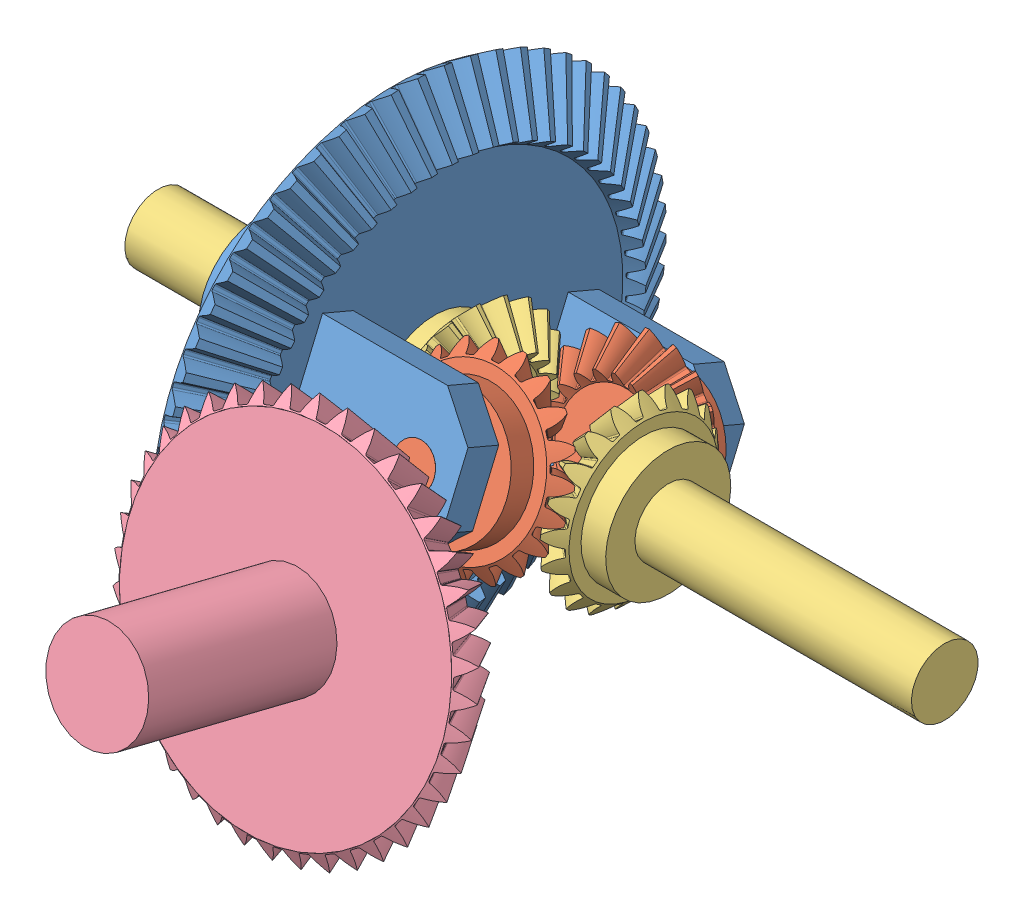
SolidWorks assembly Differential Assembly, configuration Default. Lengths in mm.
Overall size (471.43 398.88 514.12).
7 component instances, 5 part files, 17 mates.
Components (placement in the parent):
- G 60-1: G 60 [Default] at (14.6727 184.1865 258.052) x (1 0 0) z (0 -0.920286 0.391245) size (198.85 304.13 304.13)
- G 20.1-1: G 20.1 [Default] at (108.5266 185.9313 262.156) x (0 -0.391245 -0.920286) z (0.04196 -0.919476 0.390901) size (61.23 106.69 106.69)
- G 20.1-2: G 20.1 [Default] at (108.5266 182.4418 253.9479) x (0 0.391245 0.920286) z (-0.04196 -0.919476 0.390901) size (61.23 106.69 106.69)
- G 20.2-1: G 20.2 [Default] at (104.067 184.1865 258.052) x (1 0 0) z (0 -0.412672 0.91088) size (206.95 106.69 106.69)
- G 20.2-2: G 20.2 [Default] at (112.9861 184.1865 258.052) x (-1 0 0) z (0 -0.334846 0.942273) size (206.95 106.69 106.69)
- Part3^Differential Assembly-1: Part3^Differential Assembly [Default] at origin size (350 434.54 490.09) (hidden, virtual)
- G 40-1: G 40 [Default] at (115.3737 179.9131 424.2516) x (0 -0.241209 -0.970473) z (0.825408 -0.547868 0.136172) size (157.05 212.76 212.76)
Mates (geometry in assembly coordinates):
- Coincident1: coincident aligned: circle of G 60-1; circle of G 20.1-1
- Coincident2: coincident aligned: circle of G 60-1; circle of G 20.1-2
- Coincident3: coincident anti-aligned: circle of G 60-1; circle of G 20.2-1
- Concentric2: concentric anti-aligned: cylinder of G 20.2-1 through (-127.1902 184.1865 258.052) axis (1 0 0) radius 20; cylinder of G 20.2-2 through (344.2434 184.1865 258.052) axis (-1 0 0) radius 20
- Distance3: distance = 140 mm aligned: plane of G 60-1 through (38.5266 184.1865 258.052) normal (1 0 0); plane of G 20.2-2 through (178.5266 184.1865 258.052) normal (1 0 0)
- Parallel1: parallel aligned: unknown of G 20.1-1
- Parallel4: parallel aligned: plane of G 20.1-2 through (108.5266 182.4418 253.9479) normal (-0.04196 -0.919476 0.390901)
- Angle1: planar angle = 0.785398 rad: plane of assembly through (0 0 0) normal (0 0 1); plane of G 20.2-1 through (104.067 184.1865 258.052) normal (0 -0.412672 0.91088); plane of assembly
- Angle2: planar angle = 0.785398 rad: plane of assembly through (0 0 0) normal (0 0 1); plane of assembly; plane of G 20.2-2 through (112.9861 184.1865 258.052) normal (0 -0.334846 0.942273)
- GearMate1: gear = 75 : 75 mm: cylinder of G 20.2-2 through (178.5266 184.1865 258.052) axis (-1 0 0) radius 37.5; cylinder of G 20.1-1 through (108.5266 211.5737 322.472) axis (0 -0.391245 -0.920286) radius 37.5
- GearMate2: gear = 75 : 75 mm: cylinder of G 20.1-1 through (108.5266 211.5737 322.472) axis (0 -0.391245 -0.920286) radius 37.5; cylinder of G 20.2-1 through (38.5266 184.1865 258.052) axis (1 0 0) radius 37.5
- GearMate3: gear = 75 : 75 mm: cylinder of G 20.2-2 through (178.5266 184.1865 258.052) axis (-1 0 0) radius 37.5; cylinder of G 20.1-2 through (108.5266 156.7994 193.6319) axis (0 0.391245 0.920286) radius 37.5
- GearMate4: gear = 75 : 75 mm: cylinder of G 20.2-1 through (38.5266 184.1865 258.052) axis (1 0 0) radius 37.5; cylinder of G 20.1-2 through (108.5266 156.7994 193.6319) axis (0 0.391245 0.920286) radius 37.5
- Coincident13: coincident aligned: circle of G 60-1; circle of Part3^Differential Assembly-1
- GearMate5: gear = 20 : 10 mm: cylinder of G 20.2-2 through (344.2434 184.1865 258.052) axis (-1 0 0) radius 20; cylinder of G 20.2-1 through (-127.1902 184.1865 258.052) axis (1 0 0) radius 20
- Coincident14: coincident anti-aligned: circle of Part3^Differential Assembly-1; circle of G 40-1
- GearMate6: gear = 3 : 2 mm: cylinder of G 40-1 through (115.3737 207.9528 537.0655) axis (0 -0.241209 -0.970473) radius 30; cylinder of G 60-1 through (-77.8194 184.1865 258.052) axis (1 0 0) radius 37.5
